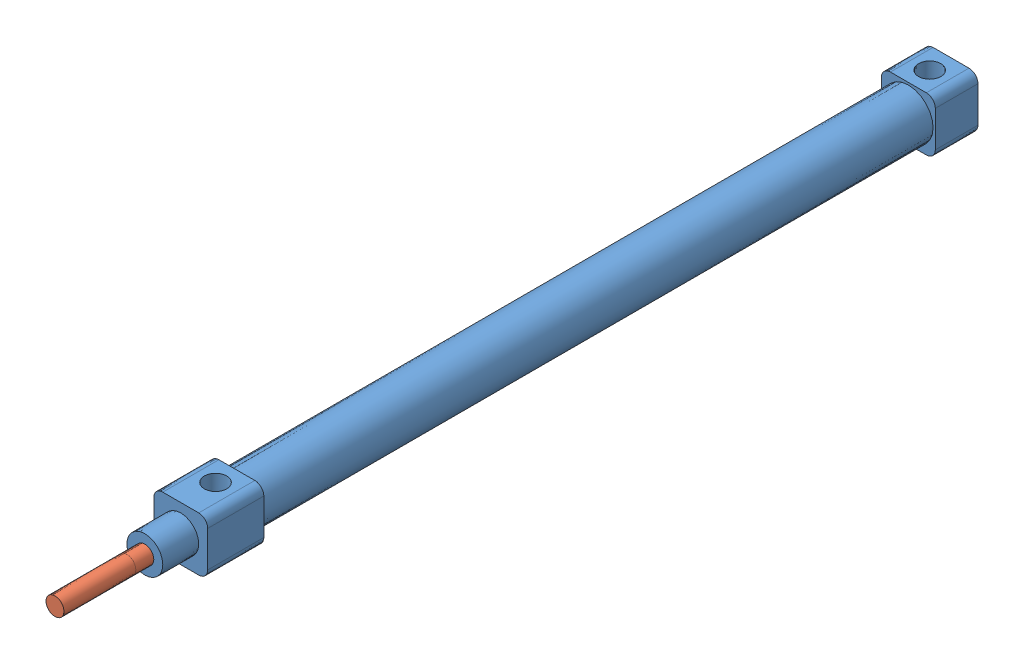
SolidWorks assembly 10x125标准型, configuration 默认. Lengths in mm.
2 component instances, 2 part files, 2 mates.
Components (placement in the parent):
- 10x125标准型-壳-1: 10x125标准型-壳 [默认] at (0.1456 -0.2548 89.75) size (12 12 179.5)
- 10x125标准型-杆-1: 10x125标准型-杆 [默认] at (0.1456 -0.2548 100.25) size (4 4 189)
Mates (geometry in assembly coordinates):
- 同心1: concentric: cylinder of assembly; cylinder of assembly; cylinder of 10x125标准型-壳-1 through (0.1456 -0.2548 84.0931) axis (0 0 1) radius 2; cylinder of 10x125标准型-杆-1 through (0.1456 -0.2548 289.25) axis (0 0 -1) radius 2
- LimitDistance1: limit distance = 20 mm: plane of assembly; plane of assembly; plane of 10x125标准型-壳-1 through (0.1456 -0.2548 269.25) normal (0 0 1); plane of 10x125标准型-杆-1 through (0.1456 -0.2548 289.25) normal (0 0 1)
